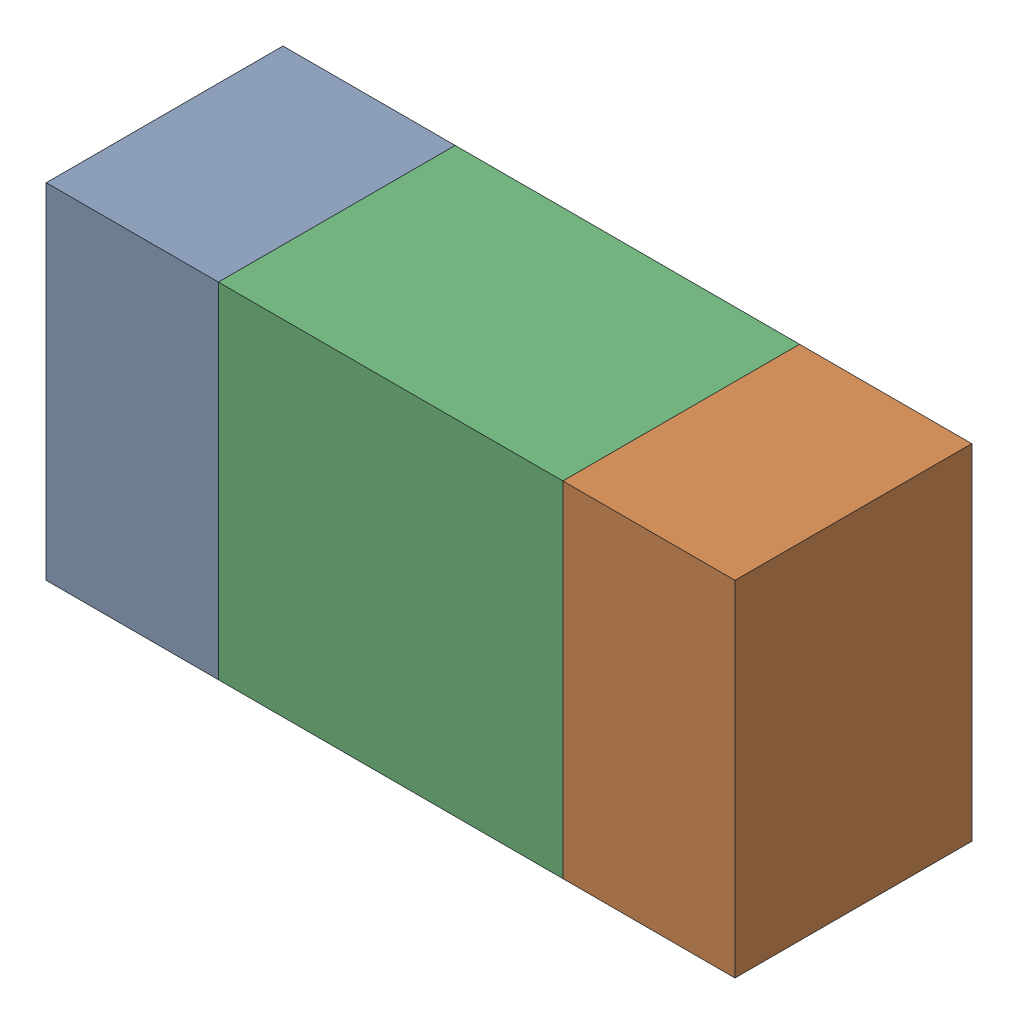
SolidWorks assembly R21, configuration ﾃﾞﾌｫﾙﾄ. Lengths in mm.
Overall size (1.6 0.8 0.55).
6 component instances, 2 part files, 0 mates.
Components (placement in the parent):
- 689261512-1: 689261512 [ﾃﾞﾌｫﾙﾄ] at (59.4001 51.2501 0) size (0.4 0.8 0.55)
  - Extruded_32-1: Extruded_32 [ﾃﾞﾌｫﾙﾄ] at origin size (0.4 0.8 0.55)
- 689261512-2: 689261512 [ﾃﾞﾌｫﾙﾄ] at (60.6001 51.2501 0) size (0.4 0.8 0.55)
  - Extruded_32-1: Extruded_32 [ﾃﾞﾌｫﾙﾄ] at origin size (0.4 0.8 0.55)
- 689261648-1: 689261648 [ﾃﾞﾌｫﾙﾄ] at (60 51.2501 0) size (0.8 0.8 0.55)
  - Extruded_33-1: Extruded_33 [ﾃﾞﾌｫﾙﾄ] at origin size (0.8 0.8 0.55)
